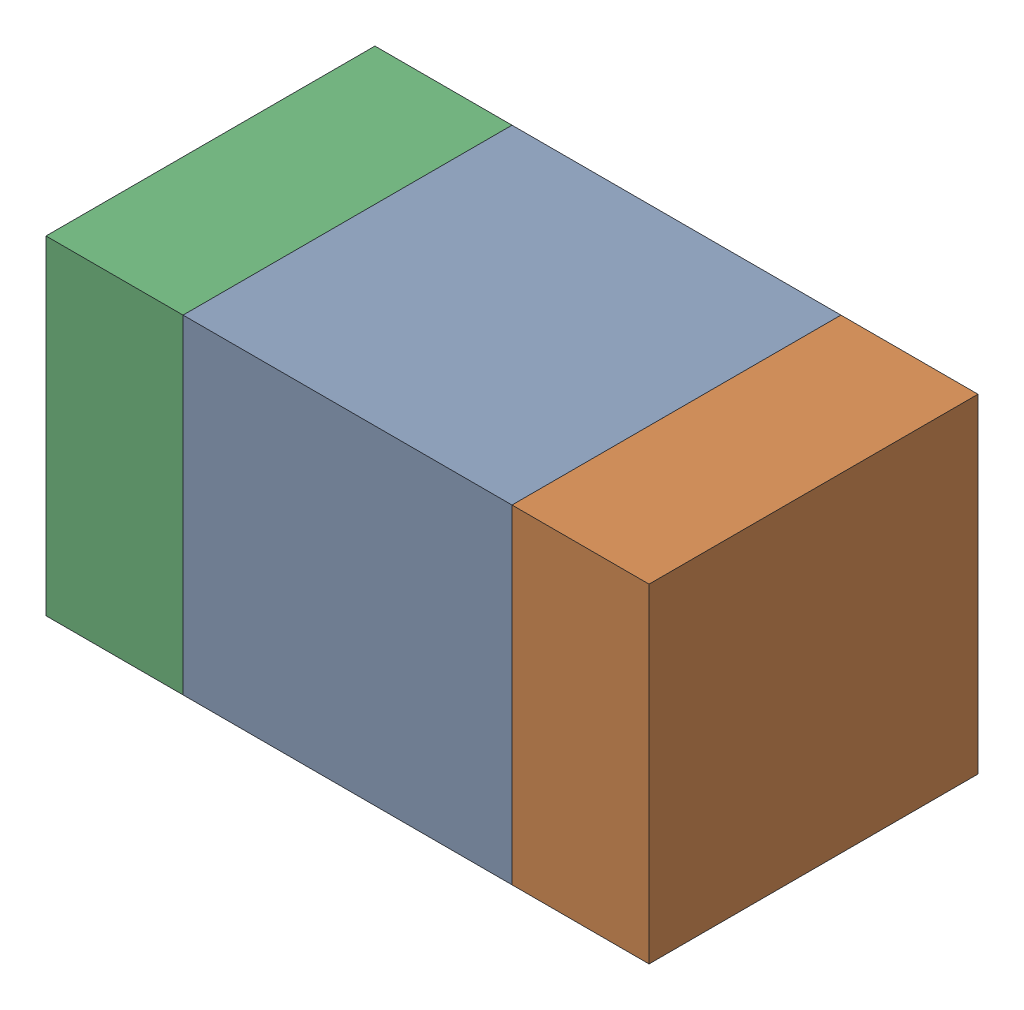
SolidWorks assembly C322_2PCB, configuration Default. Lengths in mm.
Overall size (1.1 0.6 0.6).
6 component instances, 2 part files, 0 mates.
Components (placement in the parent):
- 761606048-1: 761606048 [Default] at (136.5 85.2 -2.2638) size (0.6 0.6 0.6)
  - Extruded_9-1: Extruded_9 [Default] at origin size (0.6 0.6 0.6)
- 854785160-1: 854785160 [Default] at (136.925 85.2 -2.2638) size (0.25 0.6 0.6)
  - Extruded_19-1: Extruded_19 [Default] at origin size (0.25 0.6 0.6)
- 854785160-2: 854785160 [Default] at (136.075 85.2 -2.2638) size (0.25 0.6 0.6)
  - Extruded_19-1: Extruded_19 [Default] at origin size (0.25 0.6 0.6)
